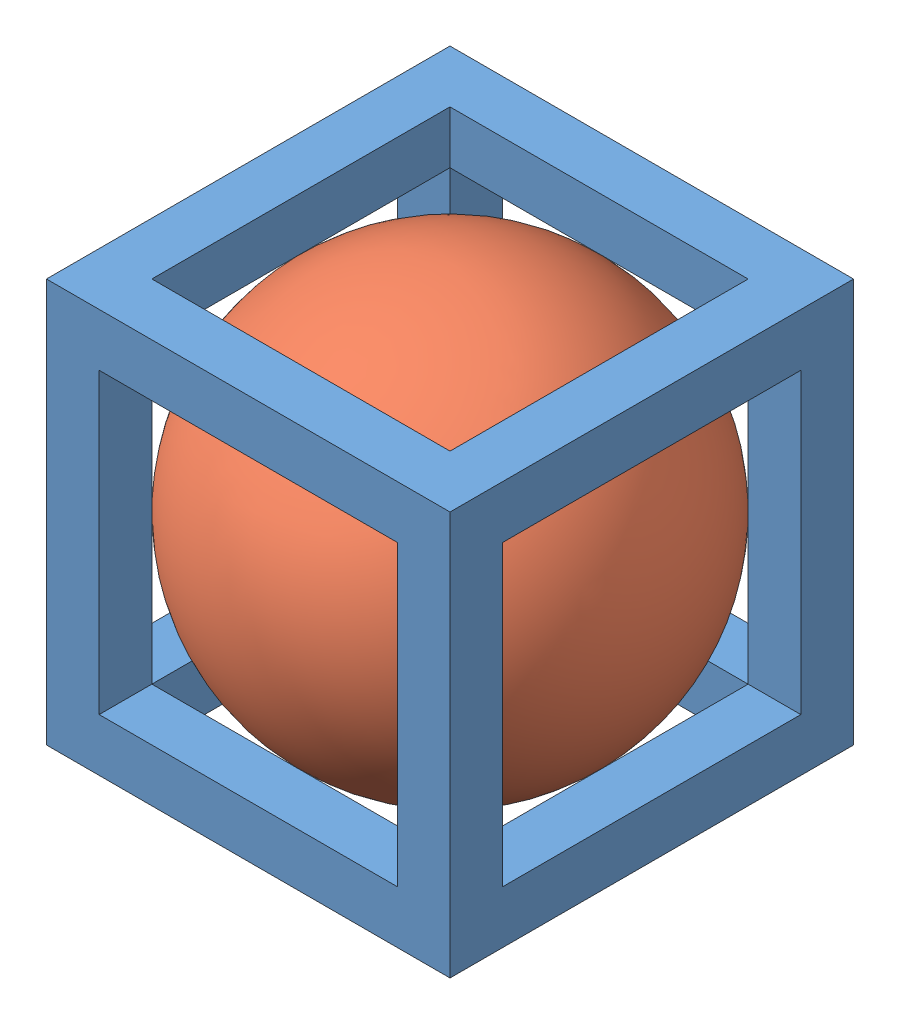
SolidWorks assembly q-ball, configuration Default. Lengths in mm.
Overall size (55.75 65.01 64.08).
2 component instances, 2 part files, 3 mates.
Components (placement in the parent):
- box-1: box [Default] at (19.7943 29.1851 22.4908) size (38.28 38.28 38.28)
- ball-1: ball [Default] at (19.7943 29.1851 41.6287) x (-0.081913 -0.564687 0.82123) z (-0.398033 0.773967 0.492488) size (40 40 40)
Mates (geometry in assembly coordinates):
- Tangent5: tangent: line of assembly; sphere of assembly; line of box-1 through (33.9364 43.3272 55.7708) axis (0 0 -1); sphere of ball-1
- Tangent6: tangent: line of assembly; sphere of assembly; line of box-1 through (5.6521 15.043 27.4908) axis (0 0 1); sphere of ball-1
- Tangent7: tangent: line of assembly; sphere of assembly; line of box-1 through (33.9364 15.043 55.7708) axis (0 1 0); sphere of ball-1
